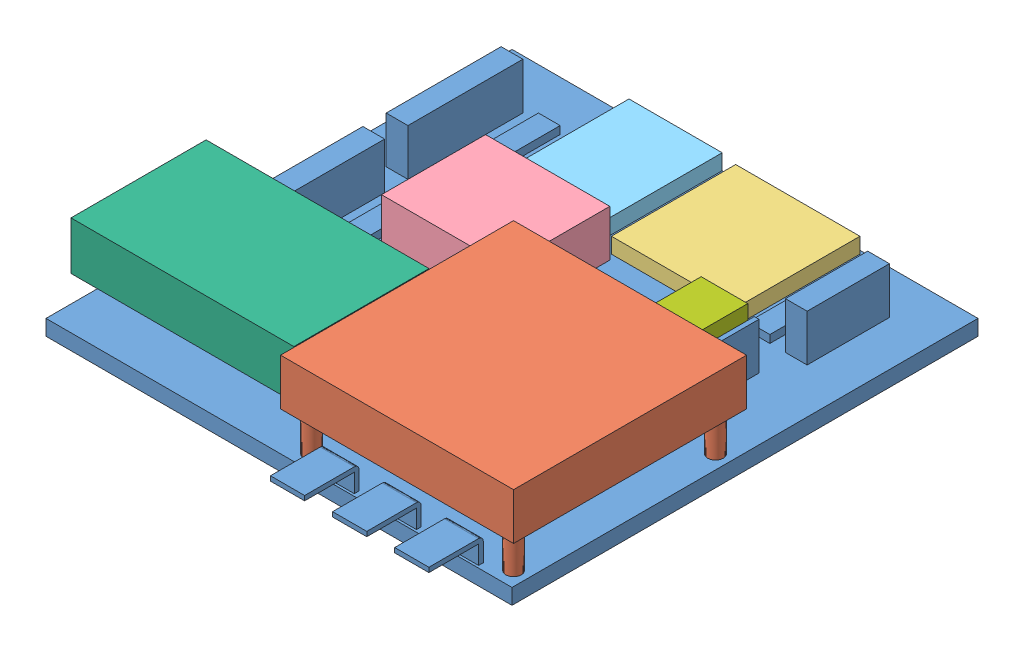
SolidWorks assembly IO Shield, configuration Default. Lengths in mm.
Overall size (76.45 24.13 83.95).
7 component instances, 7 part files, 12 mates.
Components (placement in the parent):
- IO Board-1: IO Board [Default] at (-19.8705 0.4077 9.3456) size (76.2 17.78 83.95)
- GPS-1: GPS [Default] at (-0.5665 9.2977 28.3956) size (38.1 13.97 38.1)
- Compass-1: Compass [Default] at (-10.6749 2.9477 -18.034) size (20.32 2.54 20.32)
- Override-1: Override [Default] at (-30.2811 2.9477 1.6096) x (0 0 -1) z (1 0 0) size (17.02 7.62 20.32)
- SD Logger-1: SD Logger [Default] at (-31.2201 2.9477 -19.1024) x (0 0 1) z (-1 0 0) size (19.3 2.54 15.24)
- Receiver-1: Receiver [Default] at (-38.9847 15.9017 33.0758) x (0 0 1) z (1 0 0) size (22.1 12.95 36.45)
- Fuse Holder-1: Fuse Holder [Default] at (-1.4199 2.9477 1.3094) x (0 0 1) z (-1 0 0) size (16.51 5.08 7.62)
Mates (geometry in assembly coordinates):
- Coincident1: coincident anti-aligned: plane of IO Board-1 through (-57.9705 2.9477 -28.7544) normal (0 1 0); plane of Compass-1 through (-0.5149 2.9477 -7.874) normal (0 -1 0)
- Coincident2: coincident anti-aligned: plane of IO Board-1 through (-57.9705 2.9477 -28.7544) normal (0 1 0); plane of SD Logger-1 through (-23.6001 2.9477 -28.7544) normal (0 -1 0)
- Coincident4: coincident anti-aligned: plane of Override-1 through (-20.1211 2.9477 -6.8994) normal (0 -1 0); plane of IO Board-1 through (-57.9705 2.9477 -28.7544) normal (0 1 0)
- Coincident5: coincident aligned: plane of SD Logger-1 through (-38.8401 5.4877 -28.7544) normal (0 0 -1); plane of IO Board-1 through (18.2295 2.9477 -28.7544) normal (0 0 -1)
- Parallel1: parallel aligned: plane of Override-1 through (-40.4411 10.5677 -6.8994) normal (0 0 -1); plane of IO Board-1 through (18.2295 2.9477 -28.7544) normal (0 0 -1)
- Coincident11: coincident: plane of IO Board-1 through (-57.9705 2.9477 -28.7544) normal (0 1 0); plane of GPS-1 through (15.9435 2.9477 45.9781) normal (0 -1 0)
- Width1: width: plane of IO Board-1 through (-13.5205 5.9957 46.3026) normal (-1 0 0); plane of IO Board-1 through (12.3875 5.9957 46.3026) normal (1 0 0); plane of GPS-1 through (-19.6165 16.9177 10.4181) normal (-1 0 0); plane of GPS-1 through (18.4835 16.9177 10.4181) normal (1 0 0)
- Coincident12: coincident anti-aligned: plane of Receiver-1 through (-45.271 2.9477 22.0268) normal (0 -1 0); plane of IO Board-1 through (-57.9705 2.9477 -28.7544) normal (0 1 0)
- Parallel2: parallel aligned: plane of IO Board-1 through (-57.9705 2.9477 47.4456) normal (-1 0 0); plane of Receiver-1 through (-57.209 8.0277 44.1248) normal (-1 0 0)
- Coincident13: coincident anti-aligned: plane of IO Board-1 through (-57.9705 2.9477 -28.7544) normal (0 1 0); plane of Fuse Holder-1 through (2.3901 2.9477 -6.9456) normal (0 -1 0)
- Parallel3: parallel aligned: plane of IO Board-1 through (18.2295 2.9477 47.4456) normal (1 0 0); plane of Fuse Holder-1 through (2.3901 8.0277 9.5644) normal (1 0 0)
- Coincident14: coincident aligned: plane of IO Board-1 through (18.2295 2.9477 47.4456) normal (0 0 1); plane of GPS-1 through (-19.6165 16.9177 47.4456) normal (0 0 1)
